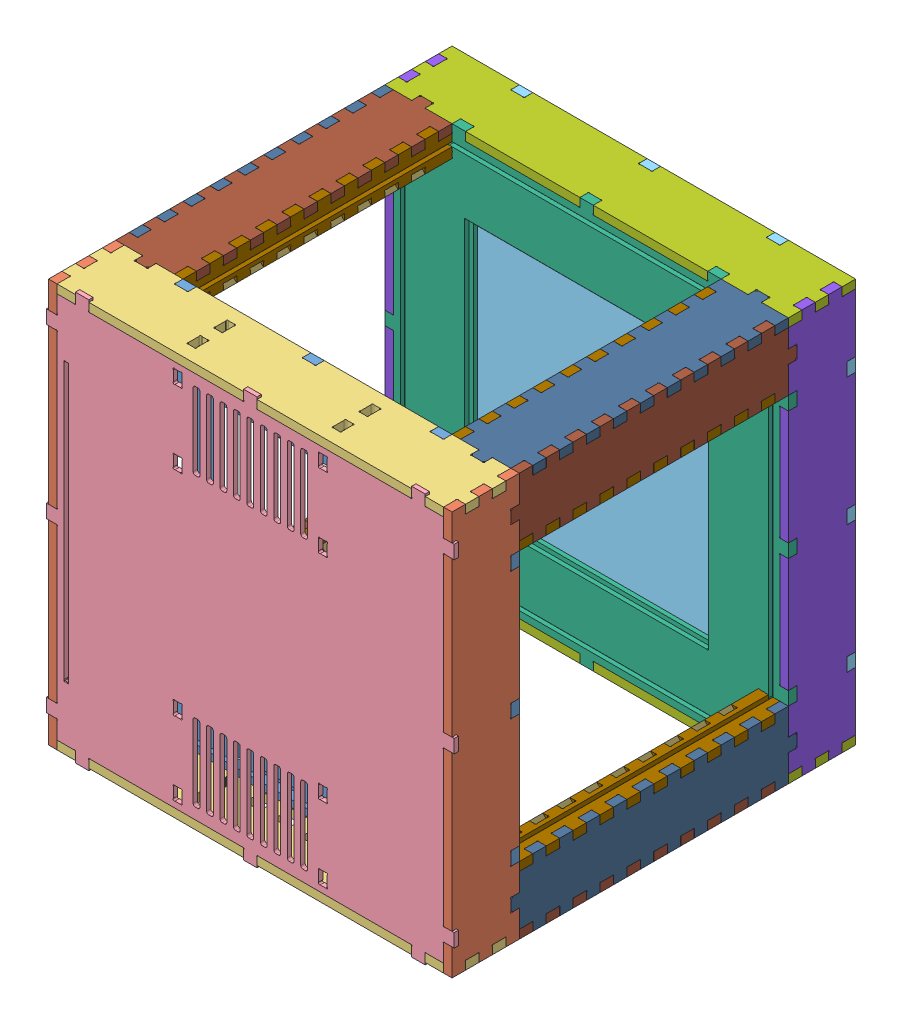
SolidWorks assembly pfc_edu_assembly, configuration Default. Lengths in mm.
Overall size (303.17 303.17 300).
38 component instances, 12 part files, 10 mates.
Components (placement in the parent):
- brain_assembly-1: brain_assembly [Default] at (54.5792 -3.8182 -48.0317) size (303.17 303.18 50)
  - pvc-025-brain02-2: pvc-025-brain02 [Default] at (-135.6596 53.2768 260.8986) size (300 300 6.35)
  - pvc-025-brain03-1: pvc-025-brain03 [Default] at (-135.6596 46.9268 254.5486) x (0 0 1) z (-1 0 0) size (50 300 6.35)
  - pvc-025-brain05-1: pvc-025-brain05 [Default] at (-142.0096 340.5768 294.5486) x (1 0 0) z (0 1 0) size (300 50 6.35)
  - pvc-025-brain03-2: pvc-025-brain03 [Default] at (157.9904 46.9268 254.5486) x (0 0 1) z (-1 0 0) size (50 300 6.35)
  - pvc-025-brain05-2: pvc-025-brain05 [slotted] at (-142.0096 46.9268 294.5486) x (1 0 0) z (0 1 0) size (300 50 6.35)
  - pvc-025-brain07-1: pvc-025-brain07 [Default] at (151.6404 53.2768 304.5486) x (-1 0 0) z (0 0 -1) size (303.17 303.17 3.17)
- res_assembly-1: res_assembly [Default] at (21.821 210.701 -49.8586) x (-1 0 0) z (0 0 1) size (300 300 50)
  - pvc-025-res03-1: pvc-025-res03 [Default] at (-184.3986 -126.0576 6.3755) size (300 300 6.35)
  - pvc-025-res01-1: pvc-025-res01 [Default] at (-184.3986 -126.0576 50.0255) size (300 300 6.35)
  - pvc-250-res02-1: pvc-250-res02 [Default] at (102.9014 167.5924 56.3755) x (-1 0 0) z (0 -1 0) size (300 50 6.35)
  - pvc-025-res04-1: pvc-025-res04 [a] at (-190.7486 161.2424 56.3755) x (0 -1 0) z (1 0 0) size (300 50 6.35)
  - pvc-250-res02-5: pvc-250-res02 [Default] at (102.9014 -126.0576 56.3755) x (-1 0 0) z (0 -1 0) size (300 50 6.35)
  - pvc-025-res04-2: pvc-025-res04 [b] at (109.2514 -126.0576 56.3755) x (0 1 0) z (-1 0 0) size (300 50 6.35)
- columns_assembly02-1: columns_assembly02 [Default] at (-58.5202 272.3493 126.3939) x (0 -1 0) z (1 0 0) size (50 212.7 50)
  - columns03-1: columns03 [a] at (-70.7593 -80.1229 14.7397) size (22.44 212.7 6.35)
  - columns03-2: columns03 [b] at (-20.7593 -80.1229 -28.9103) x (0 0 1) z (-1 0 0) size (22.44 212.7 6.35)
  - columns02-1: columns02 [Default] at (-27.1093 -80.1229 -22.5603) x (-1 0 0) z (0 0 -1) size (50 212.7 6.35)
  - columns01-1: columns01 [Default] at (-64.4093 -80.1229 -28.9103) x (0 0 1) z (-1 0 0) size (50 212.7 6.35)
  - pvc-250-column04-1: pvc-250-column04 [Default] at (-49.6377 119.8771 13.4246) x (0 -1 0) z (0.707107 0 0.707107) size (200 38.98 6.35)
- columns_assembly02-2: columns_assembly02 [Default] at (-16.6711 72.0189 126.3939) x (1 0 0) z (0 1 0) size (50 212.7 50)
  - columns03-1: columns03 [a] at (-70.7593 -80.1229 14.7397) size (22.44 212.7 6.35)
  - columns03-2: columns03 [b] at (-20.7593 -80.1229 -28.9103) x (0 0 1) z (-1 0 0) size (22.44 212.7 6.35)
  - columns02-1: columns02 [Default] at (-27.1093 -80.1229 -22.5603) x (-1 0 0) z (0 0 -1) size (50 212.7 6.35)
  - columns01-1: columns01 [Default] at (-64.4093 -80.1229 -28.9103) x (0 0 1) z (-1 0 0) size (50 212.7 6.35)
  - pvc-250-column04-1: pvc-250-column04 [Default] at (-49.6377 119.8771 13.4246) x (0 -1 0) z (0.707107 0 0.707107) size (200 38.98 6.35)
- columns_assembly02-3: columns_assembly02 [Default] at (183.6593 113.868 126.3939) x (0 1 0) z (-1 0 0) size (50 212.7 50)
  - columns03-1: columns03 [a] at (-70.7593 -80.1229 14.7397) size (22.44 212.7 6.35)
  - columns03-2: columns03 [b] at (-20.7593 -80.1229 -28.9103) x (0 0 1) z (-1 0 0) size (22.44 212.7 6.35)
  - columns02-1: columns02 [Default] at (-27.1093 -80.1229 -22.5603) x (-1 0 0) z (0 0 -1) size (50 212.7 6.35)
  - columns01-1: columns01 [Default] at (-64.4093 -80.1229 -28.9103) x (0 0 1) z (-1 0 0) size (50 212.7 6.35)
  - pvc-250-column04-1: pvc-250-column04 [Default] at (-49.6377 119.8771 13.4246) x (0 -1 0) z (0.707107 0 0.707107) size (200 38.98 6.35)
- columns_assembly02-4: columns_assembly02 [Default] at (141.8103 314.1984 126.3939) x (-1 0 0) z (0 -1 0) size (50 212.7 50)
  - columns03-1: columns03 [a] at (-70.7593 -80.1229 14.7397) size (22.44 212.7 6.35)
  - columns03-2: columns03 [b] at (-20.7593 -80.1229 -28.9103) x (0 0 1) z (-1 0 0) size (22.44 212.7 6.35)
  - columns02-1: columns02 [Default] at (-27.1093 -80.1229 -22.5603) x (-1 0 0) z (0 0 -1) size (50 212.7 6.35)
  - columns01-1: columns01 [Default] at (-64.4093 -80.1229 -28.9103) x (0 0 1) z (-1 0 0) size (50 212.7 6.35)
  - pvc-250-column04-1: pvc-250-column04 [Default] at (-49.6377 119.8771 13.4246) x (0 -1 0) z (0.707107 0 0.707107) size (200 38.98 6.35)
Mates (geometry in assembly coordinates):
- Coincident1: coincident: plane of brain_assembly-1/pvc-025-brain02-2 through (206.7809 293.6699 206.5169) normal (0 0 -1); plane of ? through (-37.439 43.1086 206.5169) normal (0 0 1)
- Coincident2: coincident: plane of brain_assembly-1/pvc-025-brain05-2 through (192.0083 43.1086 253.9031) normal (0 -1 0); plane of ? through (-87.4304 43.1086 6.5169) normal (0 -1 0)
- Coincident3: coincident: plane of brain_assembly-1/pvc-025-brain03-1 through (-87.4304 63.6699 212.3056) normal (-1 0 0); plane of ? through (-87.4304 43.1086 206.5169) normal (-1 0 0)
- Coincident4: coincident: plane of assembly; plane of assembly; plane of brain_assembly-1/pvc-025-brain05-2 through (192.0083 43.1086 253.9031) normal (0 -1 0); plane of res_assembly-1/pvc-250-res02-1 through (-81.6417 43.1086 -32.9219) normal (0 -1 0)
- Coincident5: coincident: plane of assembly; plane of assembly; plane of res_assembly-1/pvc-250-res02-5 through (-81.6417 343.1086 -32.9219) normal (0 1 0); plane of columns_assembly02-1/columns01-1 through (-43.2191 343.1086 117.0781) normal (0 1 0)
- Coincident6: coincident: plane of assembly; plane of assembly; plane of res_assembly-1/pvc-025-res01-1 through (-81.6417 293.6699 6.5169) normal (0 0 1); plane of columns_assembly02-1/columns01-1 through (-68.5529 343.1086 6.5169) normal (0 0 -1)
- Coincident7: coincident: plane of assembly; plane of assembly; plane of res_assembly-1/pvc-025-res04-2 through (-87.4304 337.3199 -34.0444) normal (-1 0 0); plane of columns_assembly02-1/columns02-1 through (-87.4304 298.8974 17.1295) normal (-1 0 0)
- Coincident8: coincident: plane of assembly; plane of assembly; plane of brain_assembly-1/pvc-025-brain03-1 through (-87.4304 343.1086 206.5169) normal (0 0 -1); plane of columns_assembly02-1/columns02-1 through (-87.4304 324.2312 206.5169) normal (0 0 1)
- Coincident9: coincident: plane of assembly; plane of assembly; plane of brain_assembly-1/pvc-025-brain05-1 through (192.0083 343.1086 253.9031) normal (0 1 0); plane of columns_assembly02-1/columns01-1 through (-43.2191 343.1086 117.0781) normal (0 1 0)
- Coincident10: coincident: plane of assembly; plane of assembly; plane of brain_assembly-1/pvc-025-brain03-1 through (-87.4304 63.6699 212.3056) normal (-1 0 0); plane of columns_assembly02-1/columns02-1 through (-87.4304 298.8974 17.1295) normal (-1 0 0)
